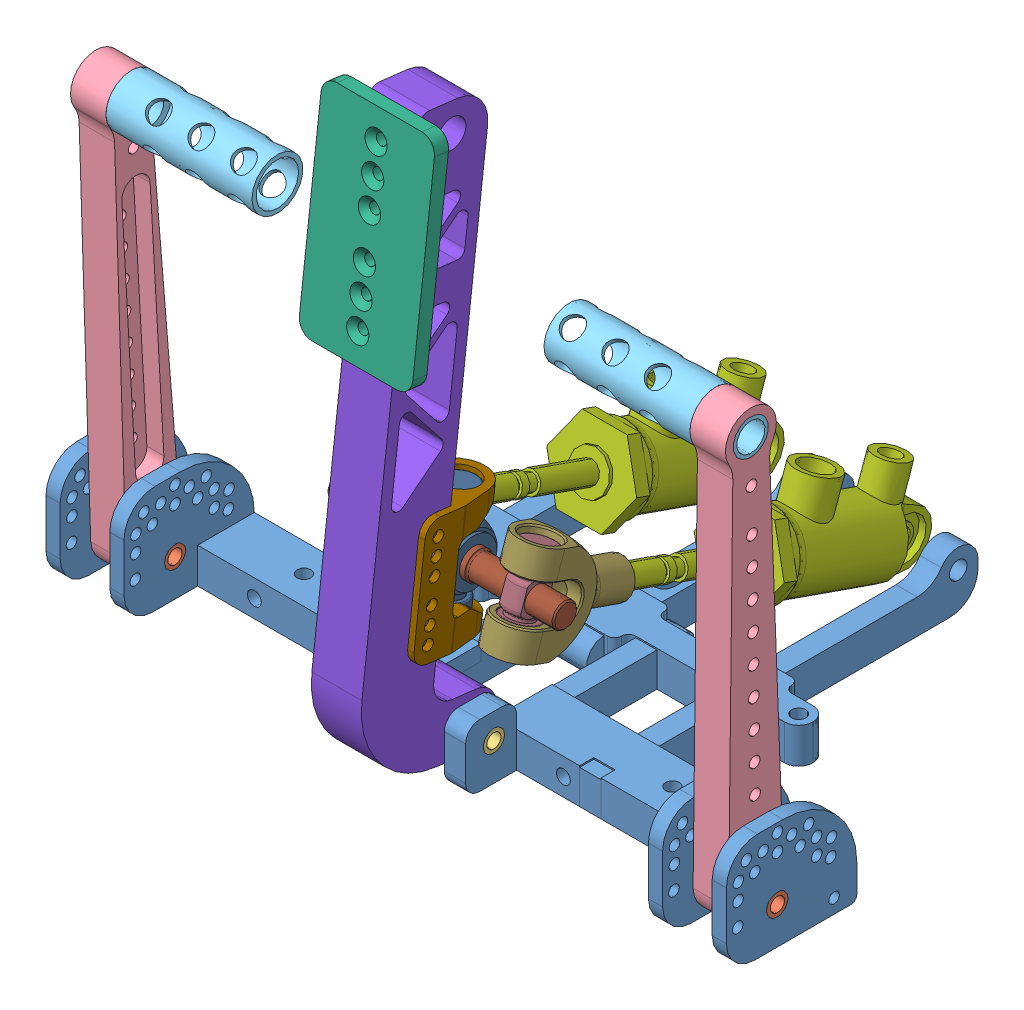
SolidWorks assembly Assem_Pedal, configuration Default. Lengths in mm.
Overall size (304.8 266.53 240.5).
38 component instances, 13 part files, 73 mates.
Components (placement in the parent):
- Short support-1: Short support [Center MC Support] at (-28.8843 -42.4949 44.1122) size (15.88 25.4 120.01)
- Short support-3: Short support [Short Support] at (-46.3468 -42.4949 44.1122) size (9.53 27.94 102.23)
- Short support-4: Short support [Short Support] at (-5.0718 -42.4949 44.1122) size (9.53 27.94 102.23)
- Short support-5: Short support [Side MC Support] at (-84.1293 -42.4949 44.1122) size (9.53 25.4 168.91)
- Short support-6: Short support [Side MC Support] at (32.7107 -42.4949 44.1122) size (9.53 25.4 168.91)
- Short support-7: Short support [Throttle and Clutch Support] at (-173.3468 -42.4949 44.1122) size (34.92 48.26 58.42)
- Short support-8: Short support [Throttle and Clutch Support] at (96.5282 -42.4949 44.1122) size (34.92 48.26 58.42)
- Short support-9: Short support [Top Left Support] at (-20.9468 -42.4949 44.1122) size (101.6 15.88 25.4)
- Short support-10: Short support [Top Center Support] at (-20.9468 -42.4949 44.1122) size (177.8 15.88 25.4)
- Short support-11: Short support [Top Right Support] at (-20.9468 -42.4949 44.1122) size (101.6 15.88 25.4)
- Bushing_0_25_long-1: Bushing_0_25_long [Default] at (104.4657 -25.9849 66.9722) x (-1 0 0) z (0 -0.609279 0.792956) size (7.94 12.7 12.7)
- Bushing_0_25_long-2: Bushing_0_25_long [Default] at (-146.3593 -25.9849 66.9722) size (7.94 12.7 12.7)
- Bushing_0_25_long-3: Bushing_0_25_long [Default] at (123.5157 -25.9849 66.9722) size (7.94 12.7 12.7)
- Bushing_0_25_long-4: Bushing_0_25_long [Default] at (-165.4093 -25.9849 66.9722) x (-1 0 0) z (0 -0.620987 0.783821) size (7.94 12.7 12.7)
- Bushing_0_375_long-1: Bushing_0_375_long [Default] at (-35.2343 -25.9849 66.9722) x (-1 0 0) z (0 -0.580939 -0.813947) size (11.11 12.7 12.7)
- Bushing_0_375_long-2: Bushing_0_375_long [Default] at (-6.6593 -25.9849 66.9722) size (11.11 12.7 12.7)
- Bushing_0_25_long-5: Bushing_0_25_long [Default] at (104.4657 -25.9849 66.9722) size (7.94 12.7 12.7)
- Bushing_0_25_long-6: Bushing_0_25_long [Default] at (123.5157 -25.9849 66.9722) x (-1 0 0) z (0 -0.924225 -0.381849) size (7.94 12.7 12.7)
- Bushing_0_25_long-7: Bushing_0_25_long [Default] at (-146.3593 -25.9849 66.9722) x (-1 0 0) z (0 0.924225 0.381849) size (7.94 12.7 12.7)
- Bushing_0_25_long-8: Bushing_0_25_long [Default] at (-165.4093 -25.9849 66.9722) size (7.94 12.7 12.7)
- Bushing_0_375_long-3: Bushing_0_375_long [Default] at (-8.1579 -25.9849 66.9722) x (-1 0 0) z (0 -0.580939 -0.813947) size (11.11 12.7 12.7)
- Bushing_0_375_long-4: Bushing_0_375_long [Default] at (-33.7357 -25.9849 66.9722) x (1 0 0) z (0 0.530439 0.847723) size (11.11 12.7 12.7)
- Throttle_Clutch_v4_p1-1: Throttle_Clutch_v4_p1 [Default] at (-163.8218 -25.9849 66.9722) x (-1 0 0) z (0 0.056284 -0.998415) size (15.88 201.55 24.76)
- Throttle_Clutch_v4_p1-2: Throttle_Clutch_v4_p1 [Default] at (121.9282 -25.9849 66.9722) x (1 0 0) z (0 -0.013354 0.999911) size (15.88 201.55 24.76)
- Throttle_Clutch_v4_p2-1: Throttle_Clutch_v4_p2 [Default] at (-163.8218 151.5333 76.9795) x (-1 0 0) z (0 0.638284 -0.769801) size (81.28 22.86 22.86)
- Throttle_Clutch_v4_p2-2: Throttle_Clutch_v4_p2 [Default] at (121.9282 151.7993 69.3465) x (1 0 0) z (0 0.577662 -0.816276) size (81.28 22.86 22.86)
- Pad_v1-1: Pad_v1 [Default] at (-46.3468 124.7192 97.7606) x (1 0 0) z (0 0.117344 0.993091) size (50.8 95.25 6.35)
- MC_1_inch-1: MC_1_inch [Default] at (12.0732 -1.4346 -33.7594) x (1 0 0) z (0 0.333291 0.942824) size (40.33 46.04 154.37)
- MC_1_inch-2: MC_1_inch [Default] at (-53.9668 -1.4346 -33.7594) x (1 0 0) z (0 0.333291 0.942824) size (40.33 46.04 154.37)
- Brake_pad_v5-1: Brake_pad_v5 [Default] at (-33.6468 -25.9849 66.9722) x (1 0 0) z (0 0.117344 0.993091) size (22.4 254 63.5)
- Balance bar-1: Balance bar [Default] at (-21.4588 35.1525 71.2504) x (1 0 0) z (0 0.993091 -0.117344) size (101.6 75.68 56.6) (flexible)
  - Balance bar_Mounting-1: Balance bar_Mounting [Default] at (0.5121 11.3466 -2.047) size (28.07 40.45 54.48)
  - Balance bar_Spherical-1: Balance bar_Spherical [Default] at (0.5121 11.3466 -2.047) x (0 0 -1) z (1 0 0) size (50.8 28.88 19.05)
  - Balance bar_Rod-1: Balance bar_Rod [Default] at (0.5121 11.3466 -2.047) x (1 0 0) z (0 0.999715 0.023893) size (101.6 12.7 12.7)
  - Balance bar_Clevis-1: Balance bar_Clevis [Default] at (-32.5079 0.9408 0.3037) x (0 0.220353 0.97542) z (-1 0 0) size (40.64 53.98 21.34)
  - Balance bar_Clevis_Spherical-1: Balance bar_Clevis_Spherical [Default] at (-32.5079 11.3466 -2.047) x (0 0.220353 0.97542) z (1 0 0) size (34.92 15.88 15.88)
  - Balance bar_Clevis-2: Balance bar_Clevis [Default] at (33.5321 0.9408 0.3037) x (0 0.220353 0.97542) z (-1 0 0) size (40.64 53.98 21.34)
  - Balance bar_Clevis_Spherical-2: Balance bar_Clevis_Spherical [Default] at (33.5321 11.3466 -2.047) x (0 0.220353 0.97542) z (1 0 0) size (34.92 15.88 15.88)
Mates (geometry in assembly coordinates):
- Coincident2: coincident anti-aligned: plane of Short support-1 through (-19.3593 -33.6049 0.2972) normal (0 0 -1); plane of ? through (67.9532 -26.6199 0.2972) normal (0 0 1)
- Coincident3: coincident anti-aligned: plane of Short support-1 through (-28.8843 -25.9849 -103.2078) normal (-1 0 0); plane of ? through (-28.8843 -42.4949 -25.1028) normal (1 0 0)
- Coincident4: coincident anti-aligned: plane of Short support-1 through (-19.3593 -33.6049 -25.1028) normal (0 1 0); plane of ? through (-28.8843 -33.6049 -25.1028) normal (0 -1 0)
- Coincident5: coincident anti-aligned: plane of Short support-6 through (32.7107 -25.9849 -103.2078) normal (-1 0 0); plane of ? through (32.7107 -42.4949 -25.1028) normal (1 0 0)
- Coincident6: coincident anti-aligned: plane of Short support-6 through (42.2357 -33.6049 0.2972) normal (0 0 -1); plane of ? through (67.9532 -26.6199 0.2972) normal (0 0 1)
- Coincident7: coincident anti-aligned: plane of Short support-6 through (42.2357 -33.6049 -25.1028) normal (0 1 0); plane of ? through (42.2357 -33.6049 -25.1028) normal (0 -1 0)
- Coincident8: coincident anti-aligned: plane of Short support-5 through (-74.6043 -33.6049 0.2972) normal (0 0 -1); plane of ? through (67.9532 -26.6199 0.2972) normal (0 0 1)
- Coincident9: coincident anti-aligned: plane of Short support-5 through (-74.6043 -25.9849 -103.2078) normal (1 0 0); plane of ? through (-74.6043 -42.4949 -25.1028) normal (-1 0 0)
- Coincident10: coincident anti-aligned: plane of Short support-5 through (-74.6043 -33.6049 -25.1028) normal (0 1 0); plane of ? through (-84.1293 -33.6049 -25.1028) normal (0 -1 0)
- Coincident11: coincident anti-aligned: plane of Short support-3 through (-36.8218 -33.6049 -25.1028) normal (0 1 0); plane of ? through (-46.3468 -33.6049 -25.1028) normal (0 -1 0)
- Coincident12: coincident anti-aligned: plane of Short support-3 through (-9.3475 -27.2549 -6.0528) normal (0 0 -1); plane of ? through (-67.9368 -26.6199 -6.0528) normal (0 0 1)
- Coincident13: coincident anti-aligned: plane of Short support-3 through (-36.8218 -25.9849 -103.2078) normal (1 0 0); plane of ? through (-36.8218 -42.4949 -25.1028) normal (-1 0 0)
- Coincident14: coincident anti-aligned: plane of Short support-4 through (4.4532 -25.9849 -103.2078) normal (1 0 0); plane of ? through (4.4532 -42.4949 -25.1028) normal (-1 0 0)
- Coincident15: coincident anti-aligned: plane of Short support-4 through (31.9275 -27.2549 -6.0528) normal (0 0 -1); plane of ? through (26.0432 -26.6199 -6.0528) normal (0 0 1)
- Coincident16: coincident anti-aligned: plane of Short support-4 through (4.4532 -33.6049 -25.1028) normal (0 1 0); plane of ? through (4.4532 -33.6049 -25.1028) normal (0 -1 0)
- Coincident17: coincident anti-aligned: plane of Short support-4 through (4.4532 -25.9849 -103.2078) normal (1 0 0); plane of ? through (4.4532 -33.6049 31.4122) normal (-1 0 0)
- Coincident18: coincident anti-aligned: plane of Short support-4 through (4.4532 -14.5549 56.8122) normal (0 0 -1); plane of ? through (-5.0718 -26.6199 56.8122) normal (0 0 1)
- Coincident19: coincident anti-aligned: plane of Short support-4 through (4.4532 -33.6049 31.4122) normal (0 1 0); plane of ? through (-5.0718 -33.6049 31.4122) normal (0 -1 0)
- Coincident20: coincident anti-aligned: plane of Short support-3 through (-36.8218 -14.5549 56.8122) normal (0 0 -1); plane of ? through (-36.8218 -26.6199 56.8122) normal (0 0 1)
- Coincident21: coincident anti-aligned: plane of Short support-3 through (-46.3468 -25.9849 -103.2078) normal (-1 0 0); plane of ? through (-46.3468 -42.4949 31.4122) normal (1 0 0)
- Coincident22: coincident anti-aligned: plane of Short support-3 through (-36.8218 -33.6049 31.4122) normal (0 1 0); plane of ? through (-36.8218 -33.6049 31.4122) normal (0 -1 0)
- Coincident23: coincident anti-aligned: plane of Short support-7 through (-138.4218 -42.4949 31.4122) normal (1 0 0); plane of ? through (-138.4218 -26.6199 56.8122) normal (-1 0 0)
- Coincident24: coincident aligned: plane of Short support-7 through (-163.8218 -42.4949 31.4122) normal (0 0 -1); plane of ? through (-36.8218 -26.6199 31.4122) normal (0 0 -1)
- Coincident25: coincident aligned: plane of Short support-7 through (-163.8218 -42.4949 -112.0978) normal (0 -1 0); plane of ? through (-36.8218 -42.4949 31.4122) normal (0 -1 0)
- Coincident26: coincident anti-aligned: plane of Short support-8 through (96.5282 -25.9849 -103.2078) normal (-1 0 0); plane of ? through (96.5282 -26.6199 56.8122) normal (1 0 0)
- Coincident27: coincident aligned: plane of Short support-8 through (106.0532 -42.4949 -112.0978) normal (0 -1 0); plane of ? through (-5.0718 -42.4949 31.4122) normal (0 -1 0)
- Coincident28: coincident aligned: plane of Short support-8 through (106.0532 -42.4949 31.4122) normal (0 0 -1); plane of ? through (-5.0718 -26.6199 31.4122) normal (0 0 -1)
- Coincident29: coincident anti-aligned: plane of Short support-8 through (125.1032 -42.4949 51.7322) normal (-1 0 0); plane of Bushing_0_25_long-3 through (125.1032 -25.9849 66.9722) normal (1 0 0)
- Concentric1: concentric aligned: cylinder of Short support-8 through (106.0532 -25.9849 66.9722) axis (-1 0 0) radius 4.7117; cylinder of Bushing_0_25_long-3 through (131.4532 -25.9849 66.9722) axis (-1 0 0) radius 4.8387
- Concentric2: concentric aligned: cylinder of Short support-7 through (-163.8218 -25.9849 66.9722) axis (-1 0 0) radius 4.7117; cylinder of Bushing_0_25_long-2 through (-138.4218 -25.9849 66.9722) axis (-1 0 0) radius 4.8387
- Coincident30: coincident anti-aligned: plane of Short support-7 through (-144.7718 -42.4949 51.7322) normal (-1 0 0); plane of Bushing_0_25_long-2 through (-144.7718 -25.9849 66.9722) normal (1 0 0)
- Concentric3: concentric anti-aligned: cylinder of Short support-7 through (-163.8218 -25.9849 66.9722) axis (-1 0 0) radius 4.7117; cylinder of Bushing_0_25_long-4 through (-173.3468 -25.9849 66.9722) axis (1 0 0) radius 4.8387
- Concentric4: concentric anti-aligned: cylinder of Short support-8 through (106.0532 -25.9849 66.9722) axis (-1 0 0) radius 4.7117; cylinder of Bushing_0_25_long-1 through (96.5282 -25.9849 66.9722) axis (1 0 0) radius 4.8387
- Coincident32: coincident anti-aligned: plane of Short support-8 through (102.8782 -42.4949 51.7322) normal (1 0 0); plane of Bushing_0_25_long-1 through (102.8782 -25.9849 66.9722) normal (-1 0 0)
- Coincident33: coincident anti-aligned: plane of Short support-7 through (-166.9968 -42.4949 51.7322) normal (1 0 0); plane of Bushing_0_25_long-4 through (-166.9968 -25.9849 66.9722) normal (-1 0 0)
- Coincident34: coincident anti-aligned: plane of Short support-4 through (-5.0718 -25.9849 -103.2078) normal (-1 0 0); plane of Bushing_0_375_long-2 through (-5.0718 -25.9849 66.9722) normal (1 0 0)
- Concentric5: concentric aligned: cylinder of Short support-4 through (4.4532 -25.9849 66.9722) axis (-1 0 0) radius 4.7117; cylinder of Bushing_0_375_long-2 through (4.4532 -25.9849 66.9722) axis (-1 0 0) radius 4.8387
- Concentric6: concentric anti-aligned: cylinder of Short support-3 through (-36.8218 -25.9849 66.9722) axis (-1 0 0) radius 4.7117; cylinder of Bushing_0_375_long-1 through (-46.3468 -25.9849 66.9722) axis (1 0 0) radius 4.8387
- Coincident35: coincident anti-aligned: plane of Short support-3 through (-36.8218 -25.9849 -103.2078) normal (1 0 0); plane of Bushing_0_375_long-1 through (-36.8218 -25.9849 66.9722) normal (-1 0 0)
- Concentric7: concentric anti-aligned: cylinder of Bushing_0_375_long-2 through (-5.0718 -25.9849 66.9722) axis (-1 0 0) radius 3.175; cylinder of Bushing_0_375_long-3 through (-9.7454 -25.9849 66.9722) axis (1 0 0) radius 3.175
- Concentric10: concentric anti-aligned: cylinder of Bushing_0_375_long-1 through (-36.8218 -25.9849 66.9722) axis (1 0 0) radius 3.175; cylinder of Bushing_0_375_long-4 through (-32.1482 -25.9849 66.9722) axis (-1 0 0) radius 3.175
- Coincident38: coincident anti-aligned: plane of Bushing_0_25_long-4 through (-165.4093 -25.9849 66.9722) normal (1 0 0); plane of Bushing_0_25_long-8 through (-165.4093 -25.9849 66.9722) normal (-1 0 0)
- Concentric11: concentric anti-aligned: cylinder of Bushing_0_25_long-4 through (-166.9968 -25.9849 66.9722) axis (1 0 0) radius 3.175; cylinder of Bushing_0_25_long-8 through (-163.8218 -25.9849 66.9722) axis (-1 0 0) radius 3.175
- Coincident39: coincident anti-aligned: plane of Bushing_0_25_long-2 through (-146.3593 -25.9849 66.9722) normal (-1 0 0); plane of Bushing_0_25_long-7 through (-146.3593 -25.9849 66.9722) normal (1 0 0)
- Concentric12: concentric anti-aligned: cylinder of Bushing_0_25_long-2 through (-144.7718 -25.9849 66.9722) axis (-1 0 0) radius 3.175; cylinder of Bushing_0_25_long-7 through (-147.9468 -25.9849 66.9722) axis (1 0 0) radius 3.175
- Coincident40: coincident anti-aligned: plane of Bushing_0_25_long-1 through (104.4657 -25.9849 66.9722) normal (1 0 0); plane of Bushing_0_25_long-5 through (104.4657 -25.9849 66.9722) normal (-1 0 0)
- Concentric13: concentric anti-aligned: cylinder of Bushing_0_25_long-1 through (102.8782 -25.9849 66.9722) axis (1 0 0) radius 3.175; cylinder of Bushing_0_25_long-5 through (106.0532 -25.9849 66.9722) axis (-1 0 0) radius 3.175
- Concentric14: concentric anti-aligned: cylinder of Bushing_0_25_long-3 through (125.1032 -25.9849 66.9722) axis (-1 0 0) radius 3.175; cylinder of Bushing_0_25_long-6 through (121.9282 -25.9849 66.9722) axis (1 0 0) radius 3.175
- Coincident41: coincident anti-aligned: plane of Bushing_0_25_long-3 through (123.5157 -25.9849 66.9722) normal (-1 0 0); plane of Bushing_0_25_long-6 through (123.5157 -25.9849 66.9722) normal (1 0 0)
- Coincident42: coincident anti-aligned: plane of Bushing_0_25_long-6 through (121.9282 -25.9849 66.9722) normal (-1 0 0); plane of Throttle_Clutch_v4_p1-2 through (121.9282 151.7397 69.3457) normal (1 0 0)
- Concentric15: concentric aligned: cylinder of Bushing_0_25_long-6 through (115.5782 -25.9849 66.9722) axis (1 0 0) radius 4.8387; cylinder of Throttle_Clutch_v4_p1-2 through (106.0522 -25.9849 66.9722) axis (1 0 0) radius 4.7117
- Concentric16: concentric aligned: cylinder of Bushing_0_25_long-8 through (-157.4718 -25.9849 66.9722) axis (-1 0 0) radius 4.8387; cylinder of Throttle_Clutch_v4_p1-1 through (-147.9458 -25.9849 66.9722) axis (-1 0 0) radius 4.7117
- Coincident43: coincident anti-aligned: plane of Bushing_0_25_long-8 through (-163.8218 -25.9849 66.9722) normal (1 0 0); plane of Throttle_Clutch_v4_p1-1 through (-163.8218 151.4738 76.9761) normal (-1 0 0)
- Concentric17: concentric aligned: cylinder of Throttle_Clutch_v4_p1-2 through (106.0532 151.7993 69.3465) axis (1 0 0) radius 7.8105; cylinder of Throttle_Clutch_v4_p2-2 through (40.6482 151.7993 69.3465) axis (1 0 0) radius 11.43
- Coincident44: coincident aligned: plane of Throttle_Clutch_v4_p1-2 through (121.9282 151.7397 69.3457) normal (1 0 0); plane of Throttle_Clutch_v4_p2-2 through (121.9282 151.7993 69.3465) normal (1 0 0)
- Concentric18: concentric aligned: cylinder of Throttle_Clutch_v4_p1-1 through (-147.9468 151.5333 76.9795) axis (-1 0 0) radius 7.8105; cylinder of Throttle_Clutch_v4_p2-1 through (-82.5418 151.5333 76.9795) axis (-1 0 0) radius 11.43
- Coincident45: coincident aligned: plane of Throttle_Clutch_v4_p1-1 through (-163.8218 151.4738 76.9761) normal (-1 0 0); plane of Throttle_Clutch_v4_p2-1 through (-163.8218 151.5333 76.9795) normal (-1 0 0)
- Concentric22: concentric anti-aligned: cylinder of Short support-1 through (-19.3593 -25.9849 -103.2078) axis (-1 0 0) radius 3.9624; cylinder of MC_1_inch-1 through (8.8982 -25.9849 -103.2078) axis (1 0 0) radius 3.9688
- Concentric23: concentric anti-aligned: cylinder of Short support-1 through (-19.3593 -25.9849 -103.2078) axis (-1 0 0) radius 3.9624; cylinder of MC_1_inch-2 through (-57.1418 -25.9849 -103.2078) axis (1 0 0) radius 3.9688
- Distance1: distance = 33.02 mm anti-aligned: plane of MC_1_inch-1; plane of assembly through (-20.9468 0 0) normal (-1 0 0)
- Distance2: distance = 33.02 mm anti-aligned: plane of assembly through (-20.9468 0 0) normal (-1 0 0); plane of MC_1_inch-2
- Concentric24: concentric anti-aligned: cylinder of Bushing_0_375_long-3 through (-19.2704 -25.9849 66.9722) axis (1 0 0) radius 4.8387; cylinder of Brake_pad_v5-1 through (-8.2468 -25.9849 66.9722) axis (-1 0 0) radius 4.7117
- Coincident50: coincident anti-aligned: plane of Bushing_0_375_long-3 through (-9.7454 -25.9849 66.9722) normal (-1 0 0); plane of Brake_pad_v5-1 through (-9.7454 -11.94 96.0047) normal (1 0 0)
- Concentric25: concentric anti-aligned: cylinder of Pad_v1-1 through (-20.9468 194.8317 95.8703) axis (0 -0.117344 -0.993091) radius 2.413; cylinder of Brake_pad_v5-1 through (-20.9468 186.6352 26.5028) axis (0 0.117344 0.993091) radius 2.413
- Concentric26: concentric anti-aligned: cylinder of Pad_v1-1 through (-20.9468 150.6888 101.0862) axis (0 -0.117344 -0.993091) radius 2.413; cylinder of Brake_pad_v5-1 through (-20.9468 142.4923 31.7188) axis (0 0.117344 0.993091) radius 2.413
- Coincident51: coincident anti-aligned: plane of Pad_v1-1 through (-46.3468 219.3111 86.5836) normal (0 -0.117344 -0.993091); plane of Brake_pad_v5-1 through (-33.6468 -32.9341 116.3891) normal (0 0.117344 0.993091)
- Coincident52: coincident anti-aligned: plane of Brake_pad_v5-1 through (-32.1482 71.4044 70.8106) normal (-1 0 0); plane of Balance bar-1/Balance bar_Mounting-1 through (-32.1482 60.6209 72.0848) normal (1 0 0)
- Concentric27: concentric anti-aligned: cylinder of Brake_pad_v5-1 through (-8.2468 47.074 81.3586) axis (-1 0 0) radius 2.413; cylinder of Balance bar-1/Balance bar_Mounting-1 through (-34.9803 47.074 81.3586) axis (1 0 0) radius 2.4765
- Concentric28: concentric anti-aligned: cylinder of Brake_pad_v5-1 through (-8.2468 21.8495 84.3391) axis (-1 0 0) radius 2.413; cylinder of Balance bar-1/Balance bar_Mounting-1 through (-34.9803 21.8495 84.3391) axis (1 0 0) radius 2.4765
- Concentric30: concentric aligned: cylinder of MC_1_inch-2 through (-53.9668 21.4436 30.9594) axis (0 -0.333291 -0.942824) radius 4.7625; cylinder of Balance bar-1/Balance bar_Clevis-1 through (-53.9668 35.3438 70.2805) axis (0 -0.333291 -0.942824) radius 3.9688
- Concentric31: concentric aligned: cylinder of MC_1_inch-1 through (12.0732 21.4436 30.9594) axis (0 -0.333291 -0.942824) radius 4.7625; cylinder of Balance bar-1/Balance bar_Clevis-2 through (12.0732 35.3438 70.2805) axis (0 -0.333291 -0.942824) radius 3.9688
- Coincident54: coincident anti-aligned: plane of Bushing_0_375_long-4 through (-32.1482 -25.9849 66.9722) normal (1 0 0); plane of Brake_pad_v5-1 through (-32.1482 71.4044 70.8106) normal (-1 0 0)
- Coincident55: coincident aligned: plane of Brake_pad_v5-1; plane of assembly through (-20.9468 0 0) normal (-1 0 0)
